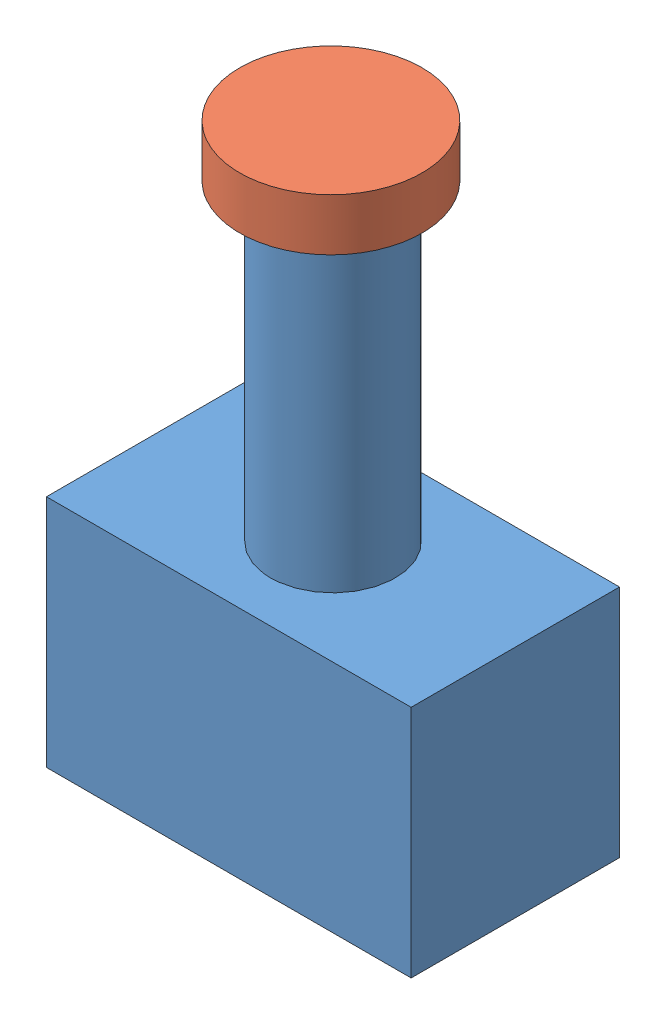
SolidWorks assembly Assem1, configuration Default. Lengths in mm.
Overall size (35 57.5 24.22).
2 component instances, 2 part files, 1 mates.
Components (placement in the parent):
- Estop-1: Estop [Default] at origin size (35 52.5 20)
- estop-top-1: estop-top [Default] at (17.364 35 -9.9351) x (-0.837169 0 -0.546944) z (-0.546944 0 0.837169) size (17.5 5 17.5)
Mates (geometry in assembly coordinates):
- Lock1: lock: unknown of Estop-1; unknown of estop-top-1
